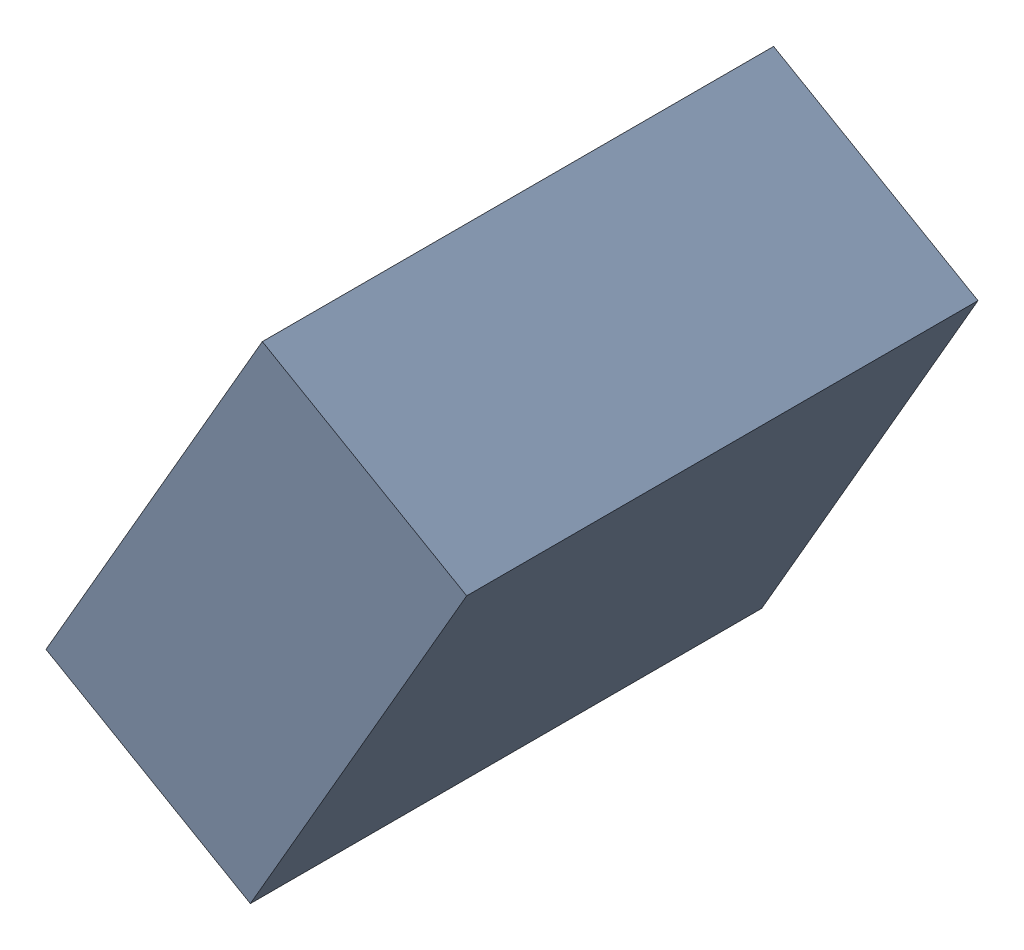
SolidWorks assembly C28_TDA3, configuration Standard. Lengths in mm.
Overall size (1.07 1.25 1.3).
2 component instances, 1 part files, 0 mates.
Components (placement in the parent):
- 885543328-1: 885543328 [Standard] at (48.3377 -30.3679 0) size (1.07 1.25 1.3)
  - Extruded_26-1: Extruded_26 [Standard] at origin size (1.07 1.25 1.3)
